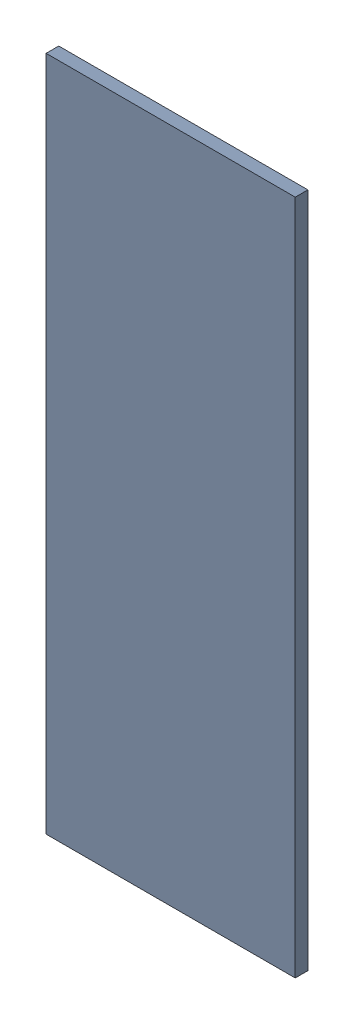
SolidWorks assembly Pad RAK4600-18(22.475mm,8.691mm) on Top Layer, configuration Predeterminado. Lengths in mm.
Overall size (0.7 1.9 0.04).
2 component instances, 1 part files, 0 mates.
Components (placement in the parent):
- Pad RAK4600-18(22.475mm,8.691mm) on Top Layer-1-1: Pad RAK4600-18(22.475mm,8.691mm) on Top Layer-1 [Predeterminado] at (-68.317 -44.187 -0.0457) size (0.7 1.9 0.04)
  - Pad RAK4600-18(22.475mm,8.691mm) on Top Layer-Part-1-1: Pad RAK4600-18(22.475mm,8.691mm) on Top Layer-Part-1 [Predeterminado] at origin size (0.7 1.9 0.04)
